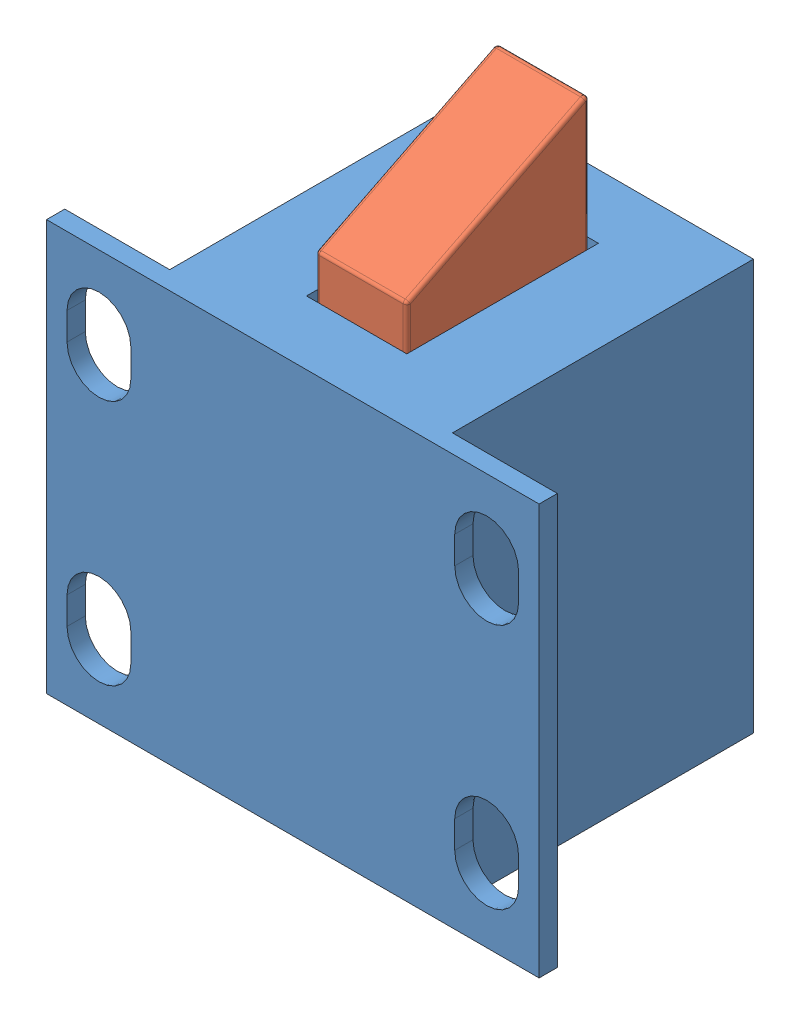
SolidWorks assembly solenoid_lock2, configuration Default. Lengths in mm.
Overall size (27 29.52 17.5).
2 component instances, 2 part files, 3 mates.
Components (placement in the parent):
- body-1: body [Default] at (11.8618 3.6944 19.2033) size (27 22.5 17.5)
- lock-1: lock [Default] at (9.3618 23.3391 24.2033) x (0 0 -1) z (0 -1 0) size (10 5 9.88)
Mates (geometry in assembly coordinates):
- Distance2: distance = 0.25 mm: plane of lock-1 through (9.3618 23.3391 24.2033) normal (-1 0 0); plane of body-1 through (9.1118 16.1944 24.4533) normal (1 0 0)
- Distance3: distance = 0.25 mm: plane of lock-1 through (14.3618 23.3391 14.2033) normal (0 0 -1); plane of body-1 through (14.6118 16.1944 13.9533) normal (0 0 1)
- LimitDistance1: limit distance = 7 mm: line of lock-1 through (14.1618 33.1944 14.4928) axis (-1 0 0); plane of body-1 through (11.8618 26.1944 19.2033) normal (0 1 0)
